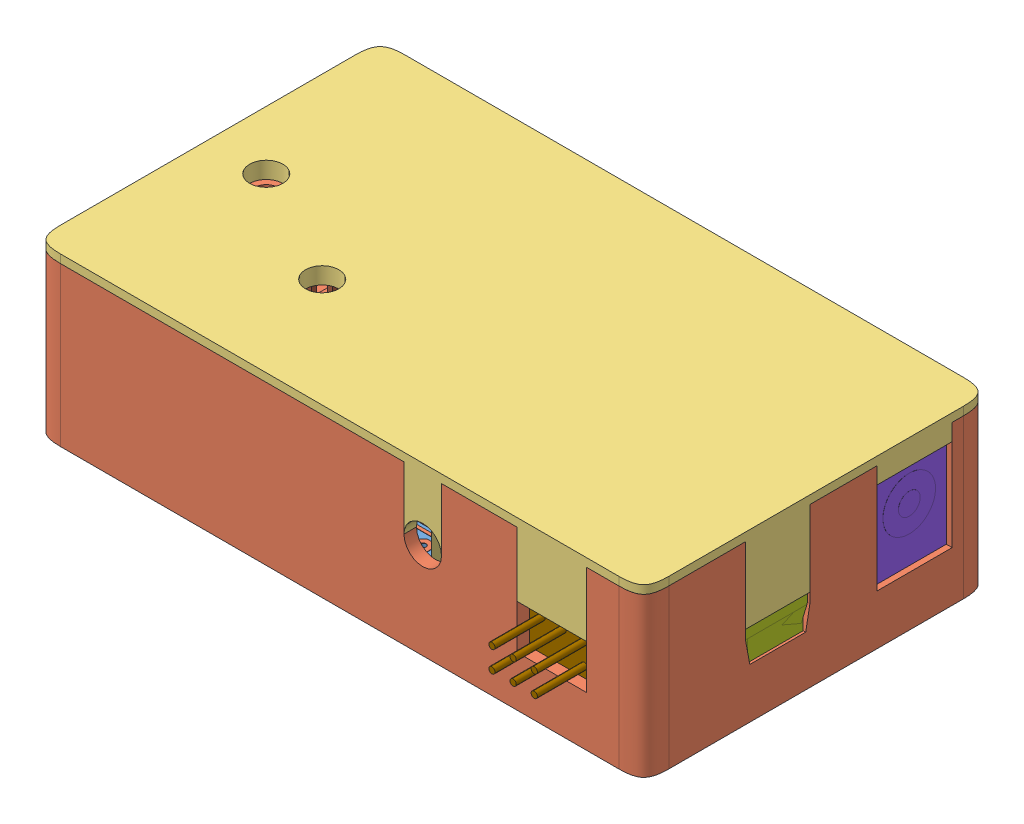
SolidWorks assembly Housing, configuration Standard. Lengths in mm.
Overall size (72.96 20.06 45.96).
40 component instances, 39 part files, 6 mates.
Components (placement in the parent):
- Door-1: Door [Standard] at (41.4 5.2 -21.75) x (0 0 1) z (0 1 0) size (44.18 59.1 15)
  - Door_Board-1: Door_Board [Standard] at origin size (37.8 57.9 1.6)
  - Door_PadsAndTracks-1: Door_PadsAndTracks [Standard] at origin size (36.15 56.35 1.67)
  - Door_IC1-1: Door_IC1 [Standard] at origin size (8.8 8.8 1.61)
  - Door_T1-1: Door_T1 [Standard] at origin size (10.42 6.73 2.38)
  - Door_T2-1: Door_T2 [Standard] at origin size (10.42 6.73 2.38)
  - Door_T3-1: Door_T3 [Standard] at origin size (10.42 6.73 2.38)
  - Door_IC2-1: Door_IC2 [Standard] at origin size (6.5 7 1.8)
  - Door_K1-1: Door_K1 [Standard] at origin size (9.35 14.52 14)
  - Door_K2-1: Door_K2 [Standard] at origin size (12.98 8.12 8.08)
  - Door_R1-1: Door_R1 [Standard] at origin size (4.7 6.5 7)
  - Door_K3-1: Door_K3 [Standard] at origin size (10.16 2.54 12)
  - Door_K4-1: Door_K4 [Standard] at origin size (2.54 7.62 12)
  - Door_D1-1: Door_D1 [Standard] at origin size (3.7 3 2.09)
  - Door_R2-1: Door_R2 [Standard] at origin size (3.2 1.6 0.61)
  - Door_R3-1: Door_R3 [Standard] at origin size (3.2 1.6 0.61)
  - Door_C1-1: Door_C1 [Standard] at origin size (3.2 1.6 0.61)
  - Door_C2-1: Door_C2 [Standard] at origin size (1.6 3.2 0.61)
  - Door_C3-1: Door_C3 [Standard] at origin size (3.2 1.6 0.61)
  - Door_K5-1: Door_K5 [Standard] at origin size (7.62 2.54 12)
  - Door_C4-1: Door_C4 [Standard] at origin size (3.2 1.6 0.61)
  - Door_R4-1: Door_R4 [Standard] at origin size (3.2 1.6 0.61)
  - Door_C5-1: Door_C5 [Standard] at origin size (1.6 3.2 0.61)
  - Door_K6-1: Door_K6 [Standard] at origin size (2.54 10.16 12)
  - Door_IC3-1: Door_IC3 [Standard] at origin size (10.4 7.8 2.1)
  - Door_K8-1: Door_K8 [Standard] at origin size (7.79 9.25 3.92)
  - Door_C6-1: Door_C6 [Standard] at origin size (1.6 3.2 0.61)
  - Door_R5-1: Door_R5 [Standard] at origin size (3.2 1.6 0.61)
  - Door_R6-1: Door_R6 [Standard] at origin size (3.2 1.6 0.61)
  - Door_R7-1: Door_R7 [Standard] at origin size (3.2 1.6 0.61)
  - Door_C7-1: Door_C7 [Standard] at origin size (3.2 1.6 0.61)
  - Door_C8-1: Door_C8 [Standard] at origin size (1.6 3.2 0.61)
  - Door_C9-1: Door_C9 [Standard] at origin size (3.2 1.6 0.61)
  - Door_C10-1: Door_C10 [Standard] at origin size (3.2 1.6 0.61)
  - Door_Q1-1: Door_Q1 [Standard] at origin size (8.49 8.49 1.2)
  - Door_C11-1: Door_C11 [Standard] at origin size (1.6 3.2 0.61)
  - Door_C12-1: Door_C12 [Standard] at origin size (1.6 3.2 0.61)
  - Door_R8-1: Door_R8 [Standard] at origin size (3.2 1.6 0.61)
- Housing-Bottom-1: Housing-Bottom [Standard] at origin size (72.96 19.06 41.36)
- Housing-Top-1: Housing-Top [Standard] at (72.9 20 -41.3) x (0 0 1) z (1 0 0) size (41.36 12.43 72.96)
Mates (geometry in assembly coordinates):
- Deckungsgleich1: coincident anti-aligned: plane of Housing-Bottom-1 through (0 2 0) normal (0 1 0); plane of Door-1/Door_T2-1 through (34.865 2 -23.43) normal (0 -1 0)
- Deckungsgleich2: coincident anti-aligned: plane of Door-1/Door_K1-1 through (68.75 6.05 -36.95) normal (0 0 -1); plane of Housing-Bottom-1 through (62.9 6 -36.95) normal (0 0 1)
- Deckungsgleich3: coincident anti-aligned: plane of Housing-Bottom-1 through (71.4 2 0) normal (-1 0 0); plane of Door-1/Door_Board-1 through (71.4 4.4 -39.55) normal (1 0 0)
- Deckungsgleich4: coincident anti-aligned: plane of Housing-Bottom-1 through (71.4 2 0) normal (-1 0 0); plane of Housing-Top-1 through (71.4 19 -41.3) normal (1 0 0)
- Deckungsgleich5: coincident anti-aligned: plane of Housing-Bottom-1 through (0 2 -1.5) normal (0 0 -1); plane of Housing-Top-1 through (72.9 19 -1.5) normal (0 0 1)
- Deckungsgleich6: coincident anti-aligned: plane of Housing-Bottom-1 through (0 19 0) normal (0 1 0); plane of Housing-Top-1 through (72.9 19 -41.3) normal (0 -1 0)
